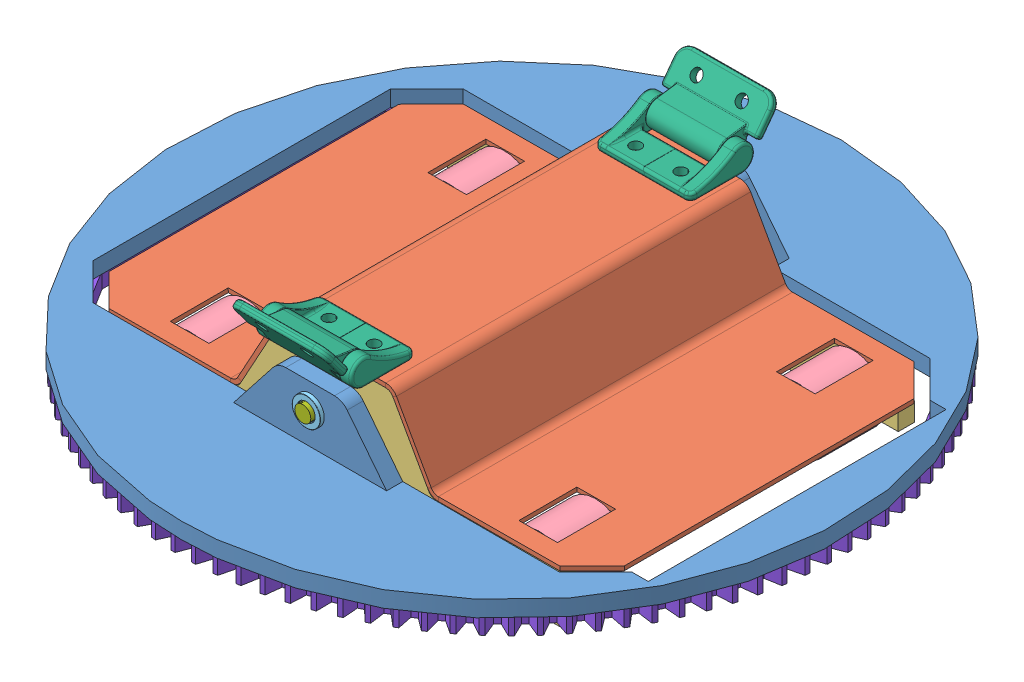
SolidWorks assembly DIAGNOSTIC, GYRO, TOP ASSY, configuration Default. Lengths in mm.
Overall size (260.35 81.68 260.35).
21 component instances, 8 part files, 7 mates.
Components (placement in the parent):
- DIAGNOSTIC, Rotary Baseplate-1: DIAGNOSTIC, Rotary Baseplate [Default] at (-48.3384 39.11 -1.0632) size (260.35 28.57 260.35)
- DIAGNOSTIC, DYNO, TOP ASSY-1: DIAGNOSTIC, DYNO, TOP ASSY [Default] at (79.4318 41.1304 -63.4055) x (0.999986 0.005206 0) z (0 0 1) size (203.2 80.62 179.89)
  - DIAGNOSTIC, DYNO, CHASSIS, TOP ASSY-1: DIAGNOSTIC, DYNO, CHASSIS, TOP ASSY [Default] at (-124.166 -14.4263 81.7928) size (203.2 49.28 139.7)
    - DIAGNOSTIC, DYNO, TOP Cover-1: DIAGNOSTIC, DYNO, TOP Cover [Default] at (-3.5138 16.2458 -19.4505) size (203.2 30.23 139.7)
    - DIAGNOSTIC, DYNO, PLATE, Sidewall-1: DIAGNOSTIC, DYNO, PLATE, Sidewall [Default] at (-3.5138 16.2458 47.2245) size (177.8 47.62 6.35)
    - DIAGNOSTIC, DYNO, PLATE, Sidewall-2: DIAGNOSTIC, DYNO, PLATE, Sidewall [Default] at (-3.5138 16.2458 -86.1255) size (177.8 47.62 6.35)
  - DIAGNOSTIC, DYNO, ROLLER-1: DIAGNOSTIC, DYNO, ROLLER [Default] at (-54.9341 -9.2295 113.1423) x (0.980458 0.196728 0) z (0 0 1) size (25.4 25.4 38.1)
  - DIAGNOSTIC, DYNO, ROLLER-2: DIAGNOSTIC, DYNO, ROLLER [Default] at (-54.9341 -9.2295 11.5423) x (0.995823 0.091309 0) z (0 0 1) size (25.4 25.4 38.1)
  - DIAGNOSTIC, DYNO, ROLLER-3: DIAGNOSTIC, DYNO, ROLLER [Default] at (-192.4497 -9.2295 113.1423) size (25.4 25.4 38.1)
  - DIAGNOSTIC, DYNO, ROLLER-4: DIAGNOSTIC, DYNO, ROLLER [Default] at (-192.4497 -9.2295 11.5423) x (0.999619 0.027593 0) z (0 0 1) size (25.4 25.4 38.1)
  - GYRO STATION, BEARING, MCMASTER 5905K210-1: GYRO STATION, BEARING, MCMASTER 5905K210 [5905K21] at (-127.6797 17.6945 -3.5389) size (11.11 11.11 7.94)
  - GYRO STATION, BEARING, MCMASTER 5905K210-2: GYRO STATION, BEARING, MCMASTER 5905K210 [5905K21] at (-127.6797 17.6945 128.2236) size (11.11 11.11 7.94)
  - DIAGNOSTIC, GYRO, MCMASTER HINGE-1: DIAGNOSTIC, GYRO, MCMASTER HINGE [Default] at (-144.2041 25.5974 -13.034) x (-1 0 0) z (0 1 0) size (38.06 36.58 26.44)
    - DIAGNOSTIC, GYRO, HINGE, MCMASTER 2190A210-1: DIAGNOSTIC, GYRO, HINGE, MCMASTER 2190A210 [Fixed] at (-22.0037 -21.9901 -16.7628) size (38.06 25.41 10.23)
    - DIAGNOSTIC, GYRO, HINGE, MCMASTER 2190A210-2: DIAGNOSTIC, GYRO, HINGE, MCMASTER 2190A210 [Moving] at (-22.0037 -34.3533 15.1084) x (1 0 0) z (0 0.799531 0.600625) size (38 25.4 10.21)
  - DIAGNOSTIC, GYRO, MCMASTER HINGE-2: DIAGNOSTIC, GYRO, MCMASTER HINGE [Default] at (-112.0506 25.5974 141.7635) x (1 0 0) z (0 1 0) size (38.06 36.58 26.44)
    - DIAGNOSTIC, GYRO, HINGE, MCMASTER 2190A210-1: DIAGNOSTIC, GYRO, HINGE, MCMASTER 2190A210 [Fixed] at (-22.0037 -21.9901 -16.7628) size (38.06 25.41 10.23)
    - DIAGNOSTIC, GYRO, HINGE, MCMASTER 2190A210-2: DIAGNOSTIC, GYRO, HINGE, MCMASTER 2190A210 [Moving] at (-22.0037 -34.3533 15.1084) x (1 0 0) z (0 0.799531 0.600625) size (38 25.4 10.21)
  - DIAGNOSTIC, RS-3705 MOTOR-1: DIAGNOSTIC, RS-3705 MOTOR [Default] at (-127.6797 17.6945 125.8423) x (1 0 0) z (0 1 0) size (25.4 83.31 25.4)
- DIAGNOSTIC, GYRO, Gear-1: DIAGNOSTIC, GYRO, Gear [Inch - Spur gear 10DP 100T 20PA .25FW ---S100N3.0H2.0L0.03125N] at (-48.3384 39.11 -1.0632) x (0 -1 0) z (0 0 1) size (6.35 259 259)
- GYRO STATION, BEARING, MCMASTER 5905K210-1: GYRO STATION, BEARING, MCMASTER 5905K210 [5905K21] at (-48.3384 58.16 75.9305) x (-0.473302 0.8809 0) z (0 0 1) size (11.11 11.11 7.94)
Mates (geometry in assembly coordinates):
- Width1: width: plane of DIAGNOSTIC, DYNO, TOP ASSY-1/DIAGNOSTIC, DYNO, CHASSIS, TOP ASSY-1/DIAGNOSTIC, DYNO, PLATE, Sidewall-1 through (-8.3046 45.6682 68.7868) normal (0 0 1); plane of DIAGNOSTIC, DYNO, TOP ASSY-1/DIAGNOSTIC, DYNO, CHASSIS, TOP ASSY-1/DIAGNOSTIC, DYNO, PLATE, Sidewall-2 through (-8.3046 45.6682 -70.9132) normal (0 0 -1); plane of DIAGNOSTIC, Rotary Baseplate-1 through (-140.4134 39.11 -74.0882) normal (0 0 1); plane of DIAGNOSTIC, Rotary Baseplate-1 through (-140.4134 39.11 71.9618) normal (0 0 -1)
- Coincident1: coincident anti-aligned: plane of DIAGNOSTIC, Rotary Baseplate-1 through (-48.3384 39.11 -1.0632) normal (0 -1 0); plane of DIAGNOSTIC, GYRO, Gear-1 through (-48.3384 39.11 -1.0632) normal (0 1 0)
- Concentric2: concentric anti-aligned: cylinder of DIAGNOSTIC, Rotary Baseplate-1 through (-48.3384 45.46 -1.0632) axis (0 -1 0) radius 130.175; cylinder of DIAGNOSTIC, GYRO, Gear-1 through (-48.3384 32.76 -1.0632) axis (0 1 0) radius 123.8237
- Parallel1: parallel aligned: plane of DIAGNOSTIC, Rotary Baseplate-1 through (-140.4134 39.11 71.9618) normal (0 0 -1); plane of DIAGNOSTIC, GYRO, Gear-1 through (-129.5087 39.11 87.8368) normal (0 0 -1)
- Concentric3: concentric anti-aligned: cylinder of DIAGNOSTIC, Rotary Baseplate-1 through (-48.3384 58.16 78.3118) axis (0 0 -1) radius 5.5563; cylinder of GYRO STATION, BEARING, MCMASTER 5905K210-1 through (-48.3384 58.16 79.8993) axis (0 0 1) radius 5.5563
- Coincident2: coincident aligned: plane of DIAGNOSTIC, Rotary Baseplate-1 through (-140.4134 39.11 71.9618) normal (0 0 -1); plane of GYRO STATION, BEARING, MCMASTER 5905K210-1 through (-51.4848 56.4694 71.9618) normal (0 0 -1)
- Concentric4: concentric anti-aligned: cylinder of DIAGNOSTIC, DYNO, TOP ASSY-1/DIAGNOSTIC, RS-3705 MOTOR-1 through (-48.3384 58.16 81.2328) axis (0 0 -1) radius 3.175; cylinder of GYRO STATION, BEARING, MCMASTER 5905K210-1 through (-48.3384 58.16 79.8993) axis (0 0 1) radius 4.7625
